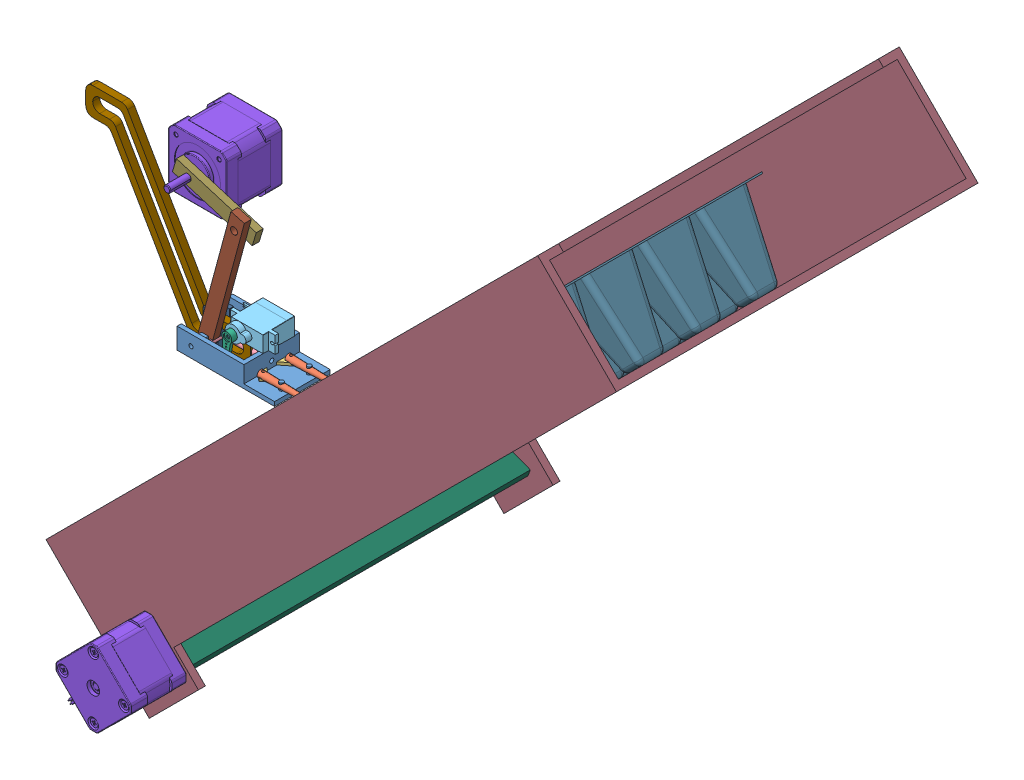
SolidWorks assembly whole, configuration Default. Lengths in mm.
Overall size (610.6 427.94 305.3).
22 component instances, 16 part files, 1 mates.
Components (placement in the parent):
- gripper_asm-1: gripper_asm [Default] at (44.0561 39.9659 134.8757) size (212.75 125 62) (flexible)
  - gripper_arm_mount-1: gripper_arm_mount [Default] at (9.2138 -11.5692 -8.133) size (70 15 40)
  - gripper_arm-1: gripper_arm [Default] at (14.2138 -6.0692 21.867) x (0 0 1) z (-1 0 0) size (5 5.06 80)
  - gripper_arm-2: gripper_arm [Default] at (14.2138 -6.0692 1.867) x (0 0 1) z (-1 0 0) size (5 5.06 80)
  - rod-1: rod [Default] at (9.9688 -6.5692 16.867) x (0.780625 0 0.625) z (0 -1 0) size (20 5 2)
  - rod-2: rod [Default] at (9.9688 -6.5692 6.867) x (0.780625 0 -0.625) z (0 -1 0) size (20 5 2)
  - rod2-1: rod2 [Default] at (8.7238 -4.0692 11.867) x (0 1 0) z (0 0 1) size (5 35 17.5)
  - Tower Pro 9g Micro Servo SG90-4: Tower Pro 9g Micro Servo SG90 [Default] at (-3.6862 9.1358 11.707) x (1 0 0) z (0 -1 0) size (36.67 31.5 22.48) (flexible)
    - Tower Pro 9g Micro Servo SG90-1: Tower Pro 9g Micro Servo SG90 [Default] at origin size (36.67 29.95 12.59)
    - SG90 plastic Horn-1: SG90 plastic Horn [Default] at (-1.405 13.16 0) x (-0.085756 0 0.996316) z (-0.996316 0 -0.085756) size (19.4 4 7.07)
  - linear_link-1: linear_link [Default] at (-13.7876 -4.4832 23.867) x (0.998475 -0.055208 0) z (-0.055208 -0.998475 0) size (20 1 5)
  - nema  17-1: nema  17 [По умолчанию] at (-43.2016 84.7808 -30.133) x (1 0 0) z (0 -1 0) size (42.3 62 51.35)
  - travel_path-1: travel_path [Default] at (-35.0247 0.9308 9.867) size (118.51 120 5)
  - guide_slider-1: guide_slider [Default] at (-30.2862 -4.0692 12.367) x (0 0 -1) z (1 0 0) size (11 30 11)
  - path_link2-1: path_link2 [Default] at (-15.356 34.547 16.867) x (0.260754 0.965405 0) z (0 0 1) size (100 10 5)
  - path_link1-2: path_link1 [Default] at (-24.0637 78.972 11.867) x (0.956893 -0.29044 0) z (0 0 1) size (60 10 5)
- tray_assembly-2: tray_assembly [Default] at (923.7517 297.8118 -131.1173) x (0 0 1) z (-0.707107 -0.707107 0) size (305.3 105 500.2)
  - seedling_tray_holder-1: seedling_tray_holder [Default] at (362.2271 326.8382 246.3572) size (260 105 500)
  - seed_tray_insert1-1: seed_tray_insert1 [Default] at (367.2271 386.8382 486.1542) x (-1 0 0) z (0 0 1) size (253.2 55 327.6)
  - tray_mover-1: tray_mover [Default] at (237.2271 329.3382 716.3572) x (1 0 0) z (0 -0.407707 0.913113) size (250 35 35)
  - nema  17-1: nema  17 [По умолчанию] at (534.2271 329.3382 716.3572) x (0 1 0) z (0 0 1) size (42.3 62 51.35)
  - cheese head screw_as-1: cheese head screw_as [AS-NZS 1427 CH - M5 x 12-N] at (228.9271 329.3382 716.3572) size (15.32 8.5 8.5)
Mates (geometry in assembly coordinates):
- Angle1: planar angle = 0.785398 rad anti-aligned: plane of gripper_asm-1/nema  17-1 through (22.0045 110.3232 136.7427) normal (1 0 0); plane of tray_assembly-2/seedling_tray_holder-1 through (108.3194 57.7357 101.1098) normal (-0.707107 0.707107 0)
